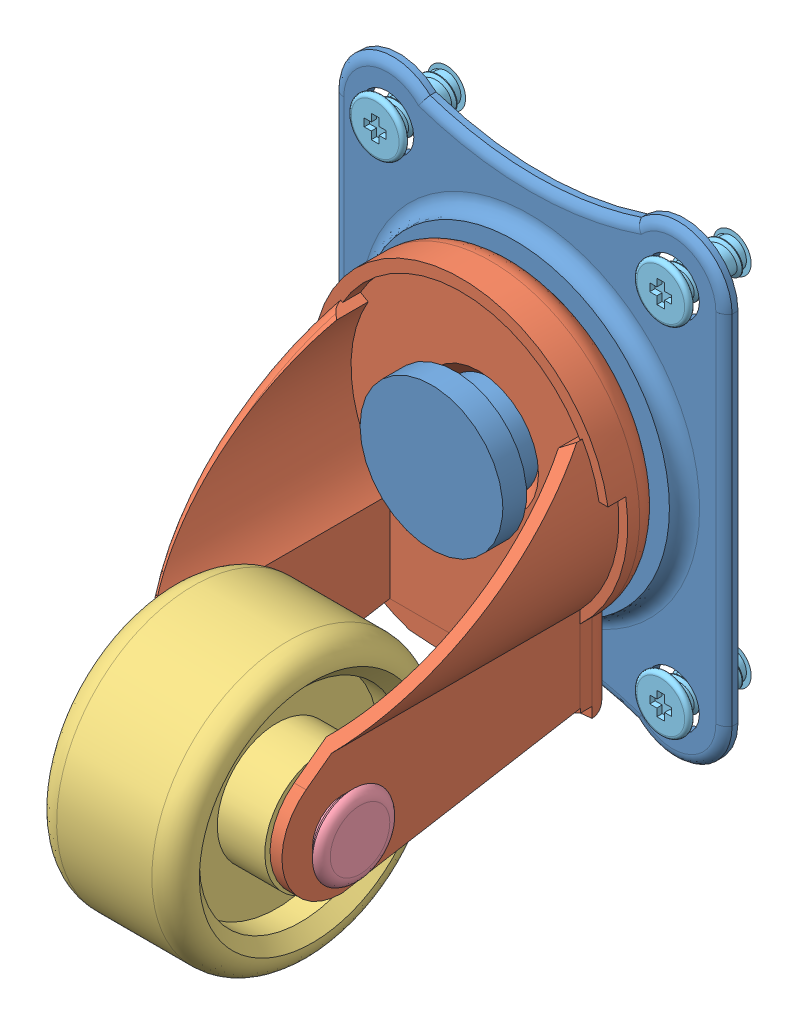
SolidWorks assembly CA, configuration Predeterminado. Lengths in mm.
Overall size (33 45.94 42.59).
9 component instances, 5 part files, 12 mates.
Components (placement in the parent):
- Caster Wheel-1: Caster Wheel [Default] at (194.2283 -297.83 183.8938) x (0 1 0) z (-1 0 0) size (45.94 37.59 33)
  - caster holder-1: caster holder [Default] at (-24.0751 44.7184 29.5137) x (1 0 0) z (0 0 -1) size (39 9.27 33)
  - holder-1: holder [Default] at (-1.5751 42.9484 46.0137) x (0 0 1) z (1 0 0) size (25 28.07 31.31)
  - caster wheel-1: caster wheel [Default] at (-15.6961 19.9484 46.0137) x (0.997275 0.073773 0) z (0 0 1) size (23 23 14)
  - Part4-1: Part4 [Default] at (-15.6961 19.9484 55.0137) x (-0.978448 0.206495 0) z (0 0 -1) size (7 7 20)
- M3x6 SelfTap Screw-1: M3x6 SelfTap Screw [Predeterminado] at (136.2146 -284.4051 140.6754) size (4.62 4.62 7)
- M3x6 SelfTap Screw-2: M3x6 SelfTap Screw [Predeterminado] at (136.2146 -314.4051 140.6754) size (4.62 4.62 7)
- M3x6 SelfTap Screw-3: M3x6 SelfTap Screw [Predeterminado] at (160.2146 -284.4051 140.6754) size (4.62 4.62 7)
- M3x6 SelfTap Screw-4: M3x6 SelfTap Screw [Predeterminado] at (160.2146 -314.4051 140.6754) size (4.62 4.62 7)
Mates (geometry in assembly coordinates):
- Concéntrica61: concentric: circle of Caster Wheel-1/caster holder-1; circle of ?
- Distancia27: distance = 0.75 mm: plane of ? through (163.0972 -311.4086 141.0494) normal (0 0 1); plane of Caster Wheel-1/caster holder-1 through (151.0972 -251.6104 140.2994) normal (0 0 1)
- Concéntrica62: concentric: circle of Caster Wheel-1/caster holder-1; circle of ?
- Distancia28: distance = 0.75 mm: plane of ? through (139.0972 -311.4086 141.0494) normal (0 0 1); plane of ? through (151.0972 -251.6104 140.2994) normal (0 0 1)
- Concéntrica63: concentric: circle of Caster Wheel-1/caster holder-1; circle of ?
- Distancia29: distance = 0.75 mm: plane of ? through (163.0972 -281.4086 141.0494) normal (0 0 1); plane of ? through (151.0972 -251.6104 140.2994) normal (0 0 1)
- Concéntrica64: concentric: circle of Caster Wheel-1/caster holder-1; circle of ?
- Distancia30: distance = 0.75 mm: plane of ? through (139.0972 -281.4086 141.0494) normal (0 0 1); plane of ? through (151.0972 -251.6104 140.2994) normal (0 0 1)
- Coincidente1: coincident: plane of Caster Wheel-1/caster holder-1 through (148.2146 -254.6069 139.6754) normal (0 0 1); plane of ?; plane of ?; plane of M3x6 SelfTap Screw-4 through (160.2146 -314.4051 139.6754) normal (0 0 -1); plane of Caster Wheel-1/caster holder-1; plane of ?; plane of ?; plane of M3x6 SelfTap Screw-3; plane of Caster Wheel-1/caster holder-1; plane of ?; plane of ?; plane of M3x6 SelfTap Screw-2; plane of Caster Wheel-1/caster holder-1; plane of ?; plane of ?; plane of M3x6 SelfTap Screw-1
- Coincidente3: coincident: plane of Caster Wheel-1/caster holder-1 through (148.2146 -254.6069 139.6754) normal (0 0 1); plane of M3x6 SelfTap Screw-3 through (160.2146 -284.4051 139.6754) normal (0 0 -1)
- Coincidente4: coincident: plane of Caster Wheel-1/caster holder-1 through (148.2146 -254.6069 139.6754) normal (0 0 1); plane of M3x6 SelfTap Screw-2 through (136.2146 -314.4051 139.6754) normal (0 0 -1)
- Coincidente5: coincident: plane of Caster Wheel-1/caster holder-1 through (148.2146 -254.6069 139.6754) normal (0 0 1); plane of M3x6 SelfTap Screw-1 through (136.2146 -284.4051 139.6754) normal (0 0 -1)
